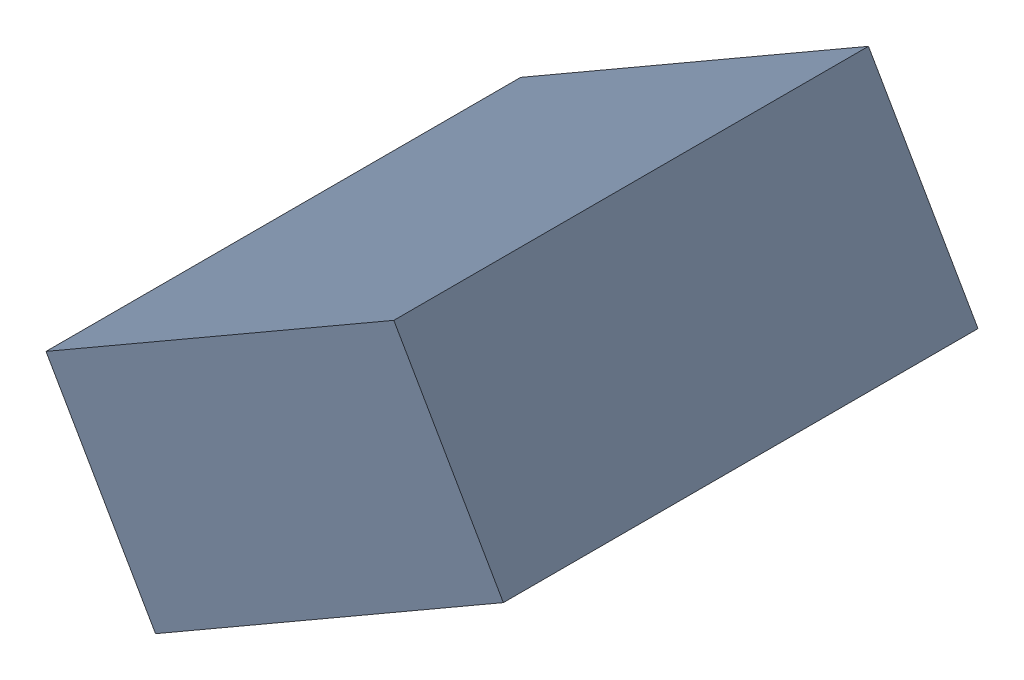
SolidWorks assembly C30_TDA5, configuration Standard. Lengths in mm.
Overall size (1.25 1.07 1.3).
2 component instances, 1 part files, 0 mates.
Components (placement in the parent):
- 885542920-1: 885542920 [Standard] at (-51.5595 -27.8323 0) size (1.25 1.07 1.3)
  - Extruded_24-1: Extruded_24 [Standard] at origin size (1.25 1.07 1.3)
